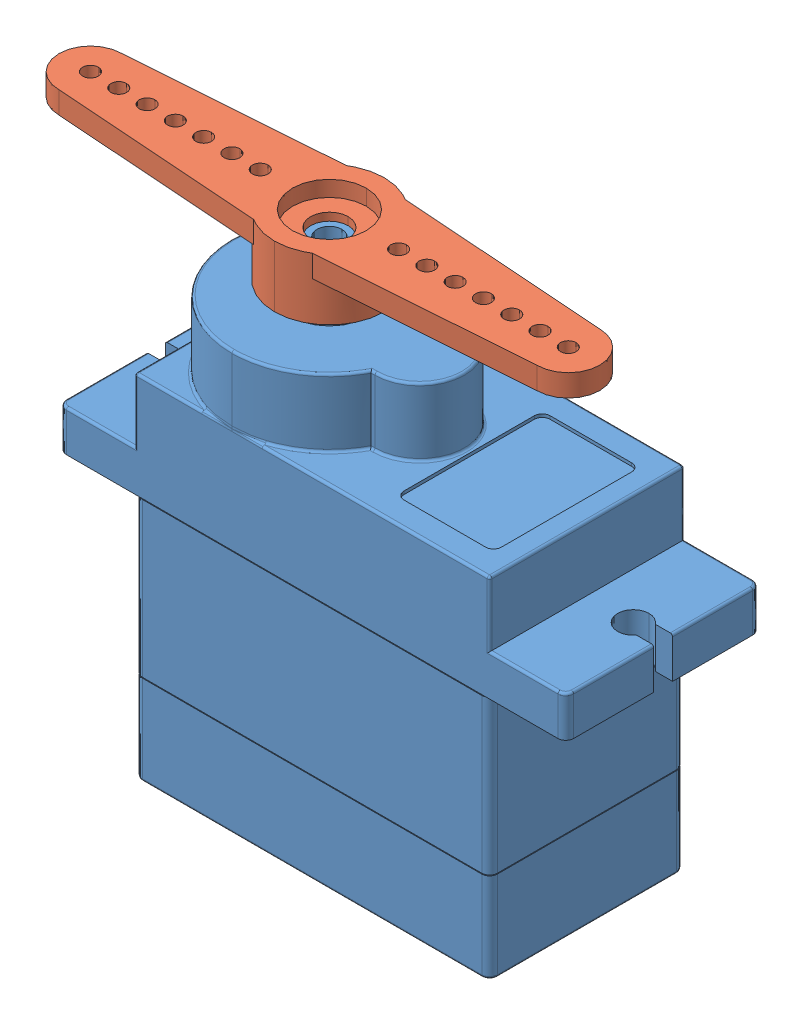
SolidWorks assembly microservoAssembly, configuration Default. Lengths in mm.
Overall size (38.45 31.3 12.41).
3 component instances, 2 part files, 0 mates.
Components (placement in the parent):
- microservoAssembly.STEP-1: microservoAssembly.STEP [Default] at origin size (38.45 31.3 12.41)
  - microservoSG90.STEP-1: microservoSG90.STEP [Default] at (7.8094 3.3655 26.0766) size (32.3 29.8 12.41)
  - microservoArm_A2.STEP-1: microservoArm_A2.STEP [Default] at (2.7094 34.6655 26.0766) x (-1 0 0.000751) z (0.000751 0 1) size (34.4 3.9 7)
